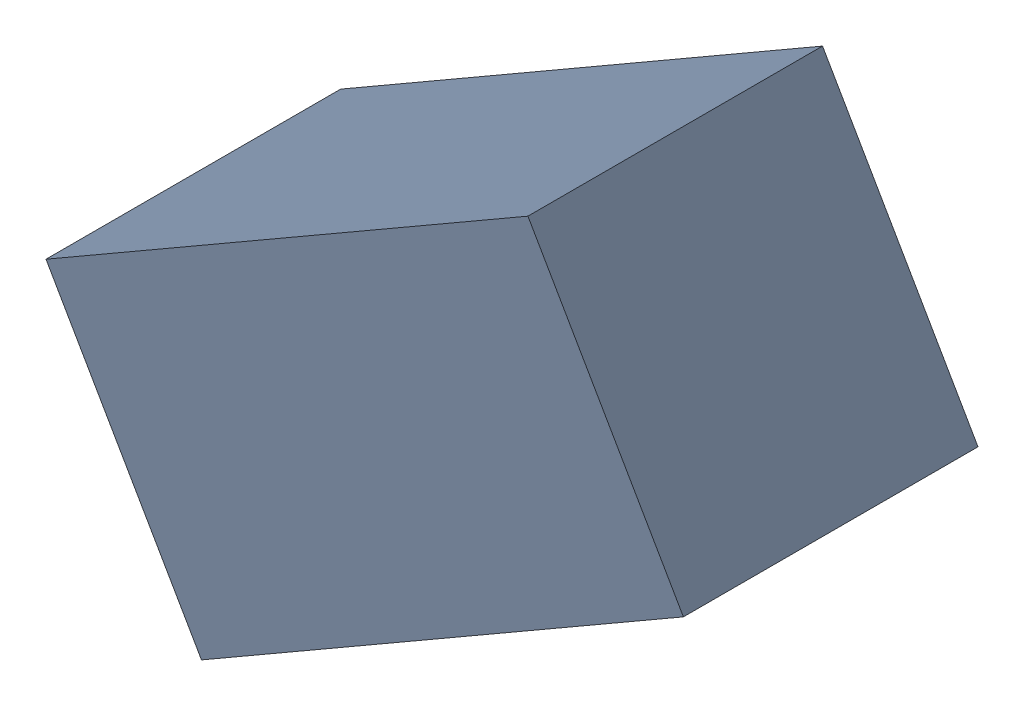
SolidWorks assembly R1_TDA2, configuration Standard. Lengths in mm.
Overall size (1.95 1.67 0.9).
2 component instances, 1 part files, 0 mates.
Components (placement in the parent):
- 885544008-1: 885544008 [Standard] at (38.8326 32.535 0) size (1.95 1.67 0.9)
  - Extruded_15-1: Extruded_15 [Standard] at origin size (1.95 1.67 0.9)
